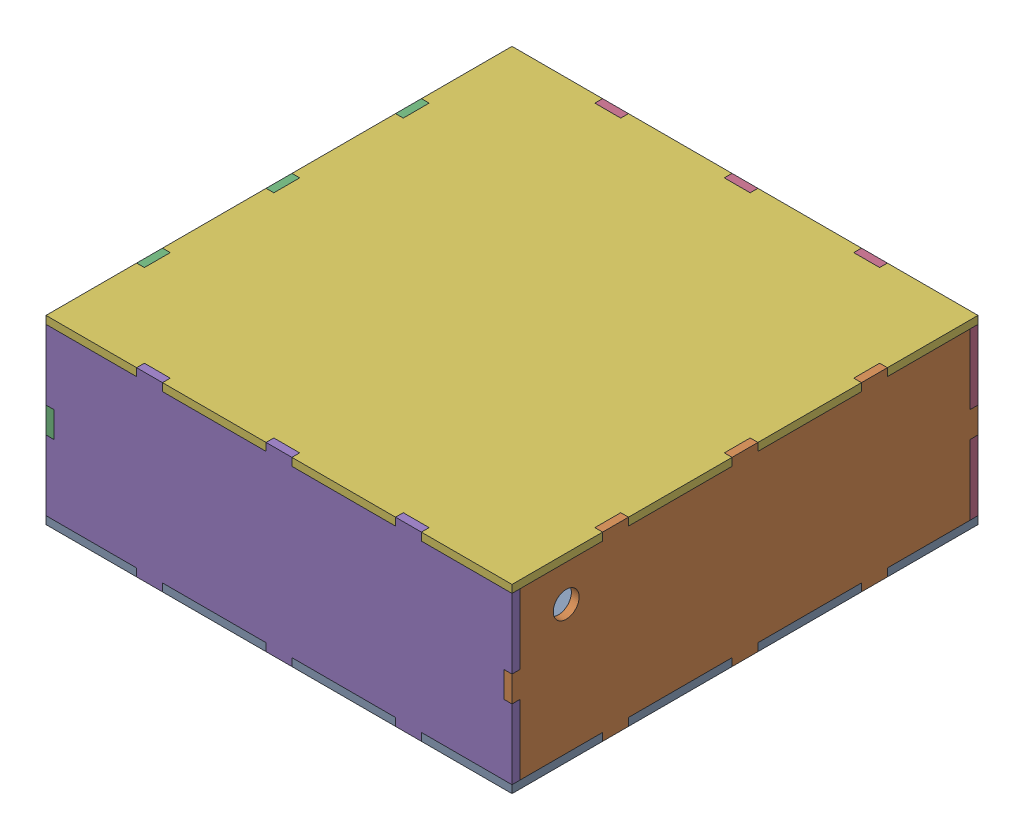
SolidWorks assembly new_assembly_model, configuration Default. Lengths in mm.
Overall size (180 70 180).
6 component instances, 4 part files, 16 mates.
Components (placement in the parent):
- buttom_part2_with extracut-1: buttom_part2_with extracut [Default] at (62.9693 42.8783 75.1328) size (180 3 180)
- Part_right_hole-1: Part_right_hole [Default] at (149.9693 77.8783 75.1328) size (3 70 180)
- Part_right_no hole-1: Part_right_no hole [Default] at (-27.0307 77.8783 75.1328) size (3 70 180)
- left part-1: left part [Default] at (62.9693 77.8783 -14.8672) size (180 70 3)
- left part-2: left part [Default] at (62.9693 77.8783 162.1328) size (180 70 3)
- buttom_part2_with extracut-2: buttom_part2_with extracut [Default] at (62.9693 109.8783 75.1328) size (180 3 180)
Mates (geometry in assembly coordinates):
- Coincident1: coincident anti-aligned: plane of buttom_part2_with extracut-1 through (62.9693 35.8783 120.1328) normal (0 0 1); plane of Part_right_hole-1 through (142.9693 77.8783 120.1328) normal (0 0 -1)
- Coincident2: coincident anti-aligned: line of buttom_part2_with extracut-1 through (149.9693 42.8783 120.1328) axis (0 0 1); line of Part_right_hole-1 through (149.9693 42.8783 130.1328) axis (0 0 -1)
- Coincident3: coincident: point of buttom_part2_with extracut-1; plane of Part_right_hole-1 through (152.9693 77.8783 75.1328) normal (1 0 0)
- Coincident4: coincident anti-aligned: plane of buttom_part2_with extracut-1 through (-27.0307 35.8783 30.1328) normal (0 0 -1); plane of Part_right_no hole-1 through (-34.0307 77.8783 30.1328) normal (0 0 1)
- Coincident5: coincident aligned: line of buttom_part2_with extracut-1 through (-24.0307 42.8783 30.1328) axis (0 0 -1); line of Part_right_no hole-1 through (-24.0307 42.8783 30.1328) axis (0 0 -1)
- Coincident6: coincident: line of buttom_part2_with extracut-1 through (-27.0307 45.8783 -14.8672) axis (0 0 1); unknown of Part_right_no hole-1
- Coincident7: coincident anti-aligned: plane of buttom_part2_with extracut-1 through (107.9693 35.8783 75.1328) normal (1 0 0); plane of left part-1 through (107.9693 77.8783 -21.8672) normal (-1 0 0)
- Coincident8: coincident aligned: line of buttom_part2_with extracut-1 through (107.9693 42.8783 -11.8672) axis (1 0 0); line of left part-1 through (107.9693 42.8783 -11.8672) axis (1 0 0)
- Coincident9: coincident aligned: line of buttom_part2_with extracut-1 through (152.9693 45.8783 -14.8672) axis (-1 0 0); line of left part-1 through (152.9693 45.8783 -14.8672) axis (-1 0 0)
- Coincident12: coincident: point of assembly; line of assembly; moEndPointRef_w of buttom_part2_with extracut-1; line of left part-2 through (7.9693 42.8783 162.1328) axis (1 0 0)
- Coincident13: coincident: plane of buttom_part2_with extracut-1 through (7.9693 35.8783 75.1328) normal (1 0 0); plane of left part-2 through (7.9693 77.8783 155.1328) normal (-1 0 0)
- Coincident14: coincident: line of Part_right_no hole-1 through (-27.0307 72.8783 162.1328) axis (0 -1 0); plane of left part-2 through (-27.0307 42.8783 165.1328) normal (-1 0 0)
- Parallel1: parallel anti-aligned: line of Part_right_no hole-1 through (-27.0307 82.8783 162.1328) axis (0 1 0); line of left part-2 through (-27.0307 109.8783 165.1328) axis (0 -1 0)
- Coincident16: coincident: plane of Part_right_no hole-1 through (-34.0307 77.8783 20.1328) normal (0 0 -1); plane of buttom_part2_with extracut-2 through (-27.0307 102.8783 20.1328) normal (0 0 1)
- Coincident17: coincident: plane of left part-2 through (7.9693 77.8783 155.1328) normal (-1 0 0); plane of buttom_part2_with extracut-2 through (7.9693 102.8783 75.1328) normal (1 0 0)
- Coincident18: coincident anti-aligned: line of left part-2 through (7.9693 109.8783 165.1328) axis (-1 0 0); line of buttom_part2_with extracut-2 through (-27.0307 109.8783 165.1328) axis (1 0 0)
